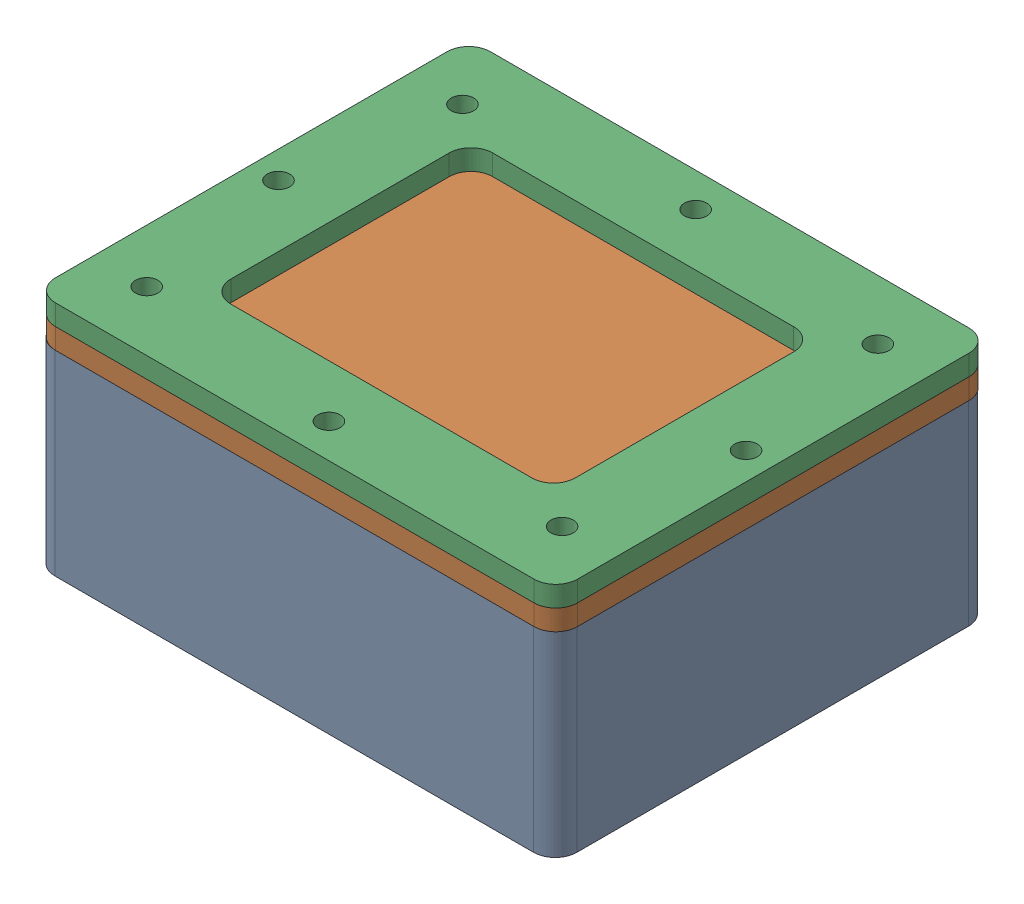
SolidWorks assembly LED_Hull_Assembly, configuration Default. Lengths in mm.
Overall size (76.28 34.58 63.5).
3 component instances, 3 part files, 6 mates.
Components (placement in the parent):
- LED_Hull-1: LED_Hull [Default] at (-16.5713 26.7081 52.1609) size (76.2 28.57 63.5)
- Acoustics_Lens-1: Acoustics_Lens [Default] at (-16.489 42.4956 52.1633) size (76.2 3 63.5)
- Acoustics_Lens_Washer-1: Acoustics_Lens_Washer [Default] at (-16.489 45.4956 52.1633) size (76.2 3 63.5)
Mates (geometry in assembly coordinates):
- Concentric1: concentric aligned: circle of LED_Hull-1; circle of Acoustics_Lens-1
- Parallel1: parallel aligned: plane of LED_Hull-1 through (21.5287 40.9956 20.4109) normal (1 0 0); plane of Acoustics_Lens-1 through (21.611 43.9956 20.4133) normal (1 0 0)
- Coincident2: coincident: plane of LED_Hull-1 through (-16.5713 40.9956 52.1609) normal (0 1 0); line of Acoustics_Lens-1 through (-51.414 40.9956 83.9133) axis (1 0 0)
- Concentric2: concentric: cylinder of Acoustics_Lens-1 through (-46.804 43.9956 29.1183) axis (0 1 0) radius 1.632; cylinder of Acoustics_Lens_Washer-1 through (-46.804 46.9956 29.1183) axis (0 1 0) radius 1.632
- Parallel2: parallel: plane of LED_Hull-1 through (21.5287 40.9956 20.4109) normal (1 0 0); plane of Acoustics_Lens_Washer-1 through (21.611 46.9956 20.4133) normal (1 0 0)
- Coincident4: coincident: line of Acoustics_Lens-1 through (-51.414 43.9956 83.9133) axis (1 0 0); plane of Acoustics_Lens_Washer-1 through (-16.489 43.9956 52.1633) normal (0 -1 0)
